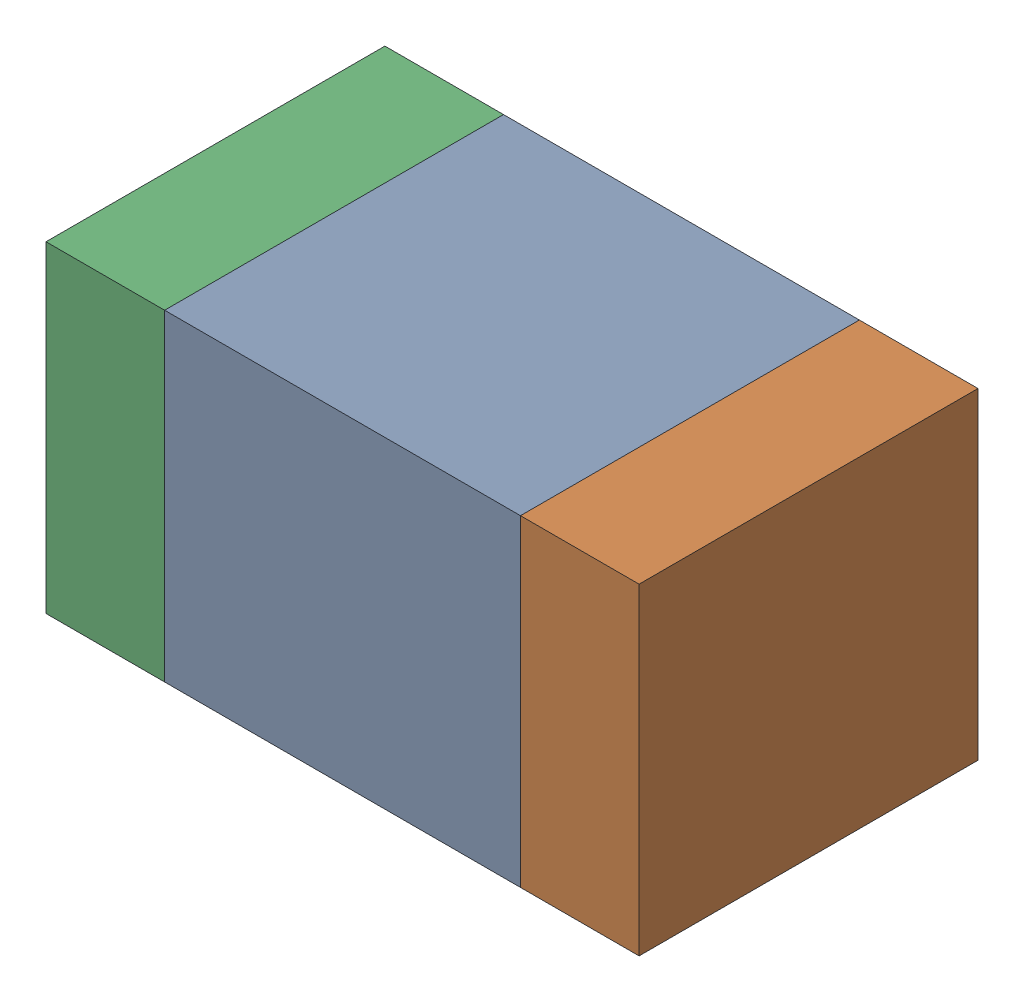
SolidWorks assembly C6-1, configuration Default. Lengths in mm.
Overall size (1.75 0.95 1).
6 component instances, 2 part files, 0 mates.
Components (placement in the parent):
- 959208800-1-1: 959208800-1 [Default] at (135.5285 81.379 0) size (1.05 0.95 1)
  - Extruded-48-1: Extruded-48 [Default] at origin size (1.05 0.95 1)
- 959208936-1-1: 959208936-1 [Default] at (136.2285 81.379 0) size (0.35 0.95 1)
  - Extruded-47-1: Extruded-47 [Default] at origin size (0.35 0.95 1)
- 959208936-1-2: 959208936-1 [Default] at (134.8286 81.379 0) size (0.35 0.95 1)
  - Extruded-47-1: Extruded-47 [Default] at origin size (0.35 0.95 1)
